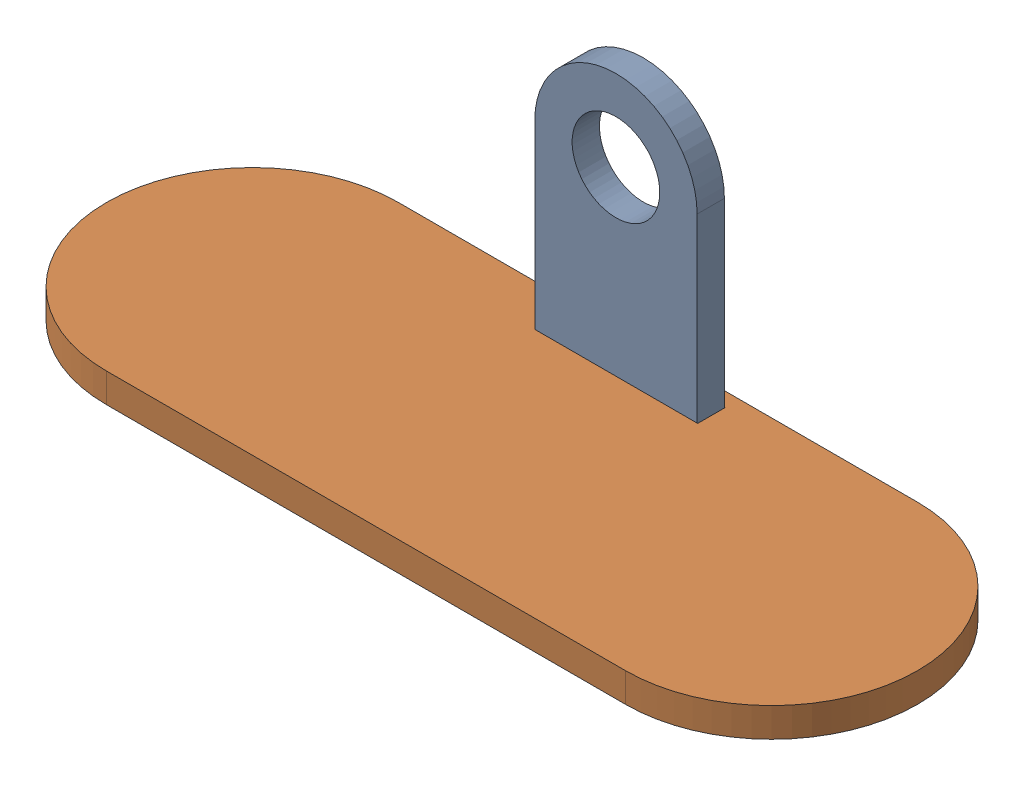
SolidWorks assembly Foot, configuration Default. Lengths in mm.
Overall size (277.8 99.8 100).
2 component instances, 2 part files, 3 mates.
Components (placement in the parent):
- Foot-001-1: Foot-001 [Default] at (660.7662 921.191 1288.8277) size (55.6 99.8 9.35)
- Foot-002-1: Foot-002 [Default] at (571.9662 849.191 1333.8777) size (277.8 10 100)
Mates (geometry in assembly coordinates):
- Coincident1: coincident: plane of Foot-001-1 through (660.7662 921.191 1298.1777) normal (0 0 1); plane of Foot-002-1 through (630.382 859.191 1298.1777) normal (0 0 -1)
- Coincident3: coincident: plane of Foot-001-1 through (632.9662 849.191 1298.1777) normal (0 -1 0); plane of Foot-002-1 through (569.382 849.191 1333.8777) normal (0 -1 0)
- Coincident5: coincident anti-aligned: plane of Foot-001-1 through (632.9662 921.191 1298.1777) normal (-1 0 0); plane of Foot-002-1 through (632.9662 859.191 1288.8777) normal (1 0 0)
